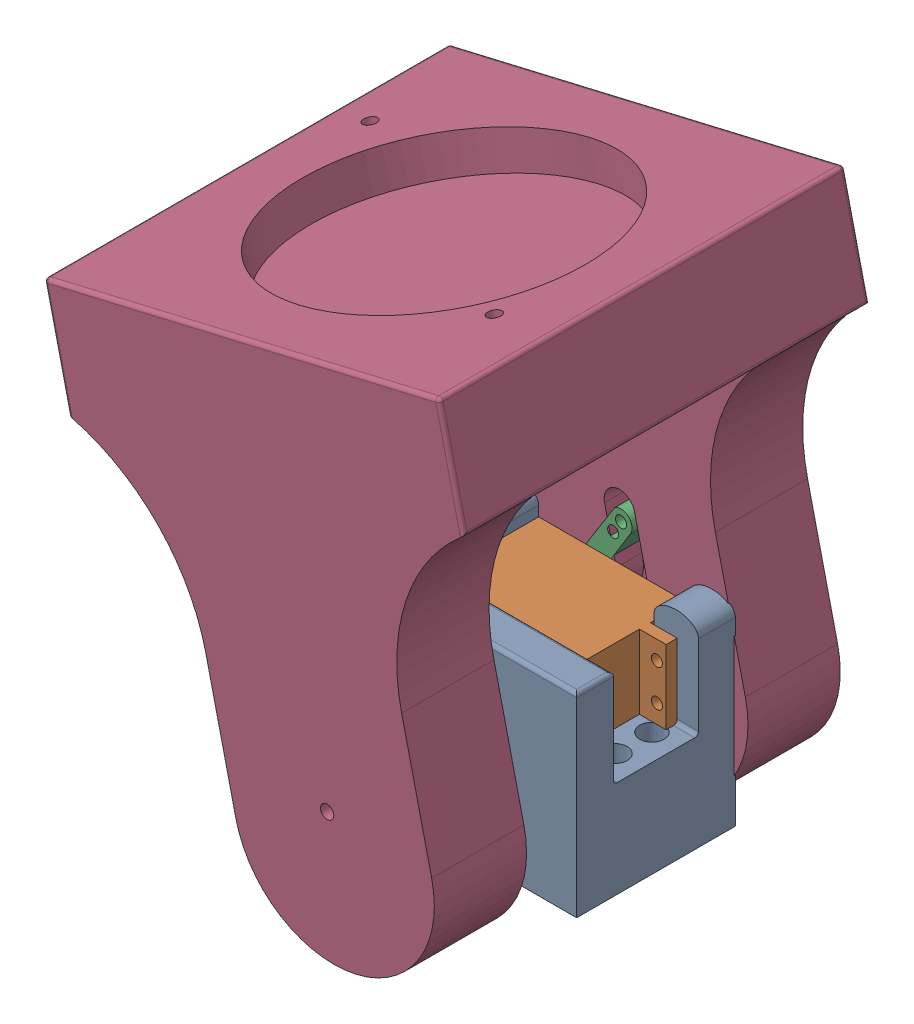
SolidWorks assembly personal Assembly, configuration Default. Lengths in mm.
Overall size (138.42 158.73 110).
4 component instances, 4 part files, 8 mates.
Components (placement in the parent):
- Final_ServoMount-1: Final_ServoMount [Default] at origin size (65 52.78 43)
- Final_servoMotor-2: Final_servoMotor [Default] at (-34.6845 -8.4477 25.4399) x (-1 0 0) z (0 0 -1) size (54.5 20 47.4)
- Final_ServoArm-1: Final_ServoArm [Default] at (-37 1.5523 -6.7) x (0.531738 0.846909 0) z (0.846909 -0.531738 0) size (34 7 15)
- Final_Platform-1: Final_Platform [Default] at (-42.6171 98.133 30.3) x (0 0 1) z (-0.228176 0.97362 0) size (110 110 137.25)
Mates (geometry in assembly coordinates):
- Coincident1: coincident anti-aligned: plane of Final_ServoMount-1 through (-53 14.3023 10) normal (0 0 1); plane of Final_servoMotor-2 through (-54.25 11.5523 10) normal (0 0 -1)
- Coincident2: coincident anti-aligned: plane of Final_ServoMount-1 through (0 14.3023 10) normal (0 0 1); plane of Final_servoMotor-2 through (0.25 11.5523 10) normal (0 0 -1)
- Coincident3: coincident anti-aligned: plane of Final_ServoMount-1 through (-47 -20.6977 33) normal (1 0 0); plane of Final_servoMotor-2 through (-47 11.5523 40.7) normal (-1 0 0)
- Concentric1: concentric anti-aligned: cylinder of Final_servoMotor-2 through (-37 1.5523 -6.7) axis (0 0 1) radius 3; cylinder of Final_ServoArm-1 through (-37 1.5523 0.3) axis (0 0 -1) radius 3
- Coincident4: coincident anti-aligned: plane of Final_servoMotor-2 through (-7 11.5523 0.3) normal (0 0 -1); plane of Final_ServoArm-1 through (-37 1.5523 0.3) normal (0 0 1)
- Coincident5: coincident anti-aligned: plane of Final_ServoMount-1 through (-6 -8.4477 33) normal (0 1 0); plane of Final_servoMotor-2 through (-34.6845 -8.4477 25.4399) normal (0 -1 0)
- Coincident6: coincident anti-aligned: plane of Final_ServoArm-1 through (-37 1.5523 -6.7) normal (0 0 -1); plane of Final_Platform-1 through (-25.0728 24.7759 -6.7) normal (0 0 1)
- Concentric2: concentric anti-aligned: cylinder of Final_ServoArm-1 through (-24.6716 21.5598 0.3) axis (0 0 -1) radius 1.5; cylinder of Final_Platform-1 through (-24.6716 21.5598 0.3) axis (0 0 1) radius 1.8
